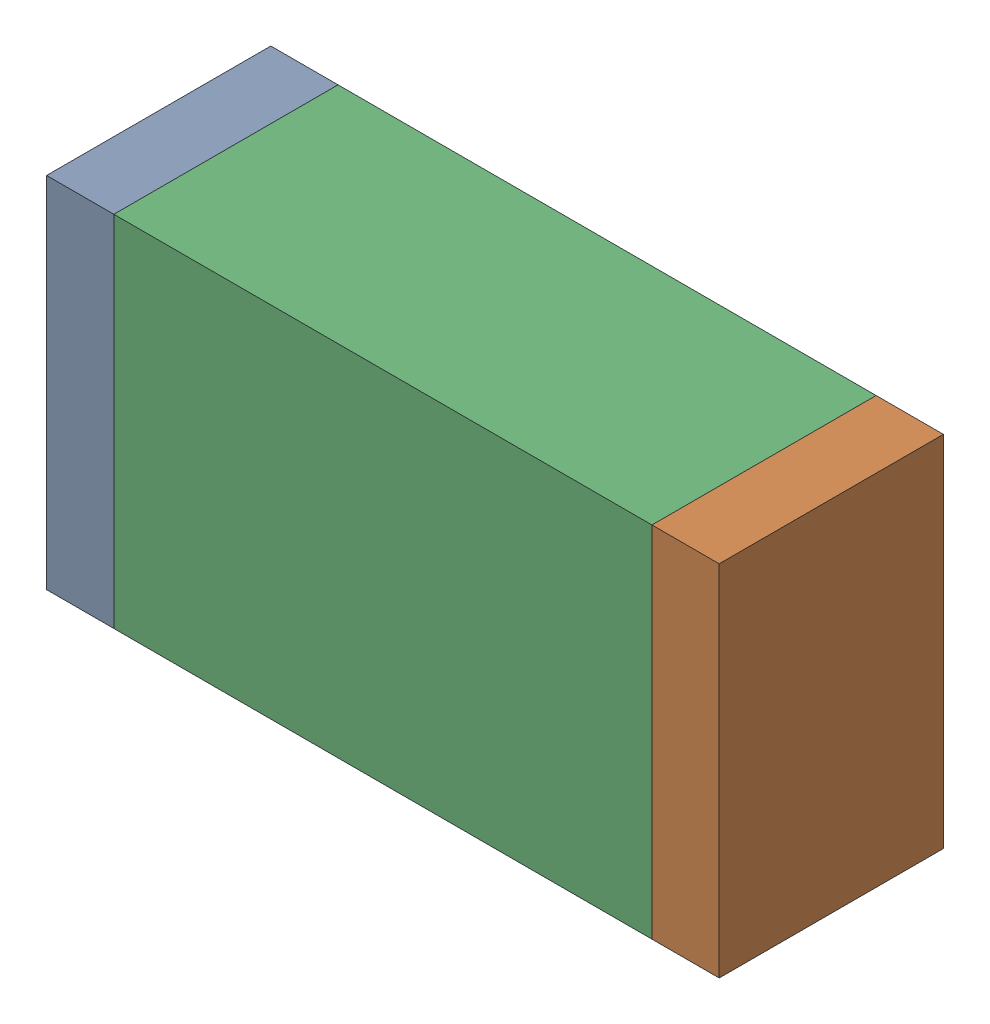
SolidWorks assembly R8, configuration Default. Lengths in mm.
Overall size (1.5 0.8 0.5).
6 component instances, 2 part files, 0 mates.
Components (placement in the parent):
- 836752496-1: 836752496 [Default] at (135.875 34.1 0) size (0.15 0.8 0.5)
  - Extruded_2-1: Extruded_2 [Default] at origin size (0.15 0.8 0.5)
- 836752496-2: 836752496 [Default] at (137.225 34.1 0) size (0.15 0.8 0.5)
  - Extruded_2-1: Extruded_2 [Default] at origin size (0.15 0.8 0.5)
- 836752368-1: 836752368 [Default] at (136.55 34.1 0) size (1.2 0.8 0.5)
  - Extruded-1: Extruded [Default] at origin size (1.2 0.8 0.5)
